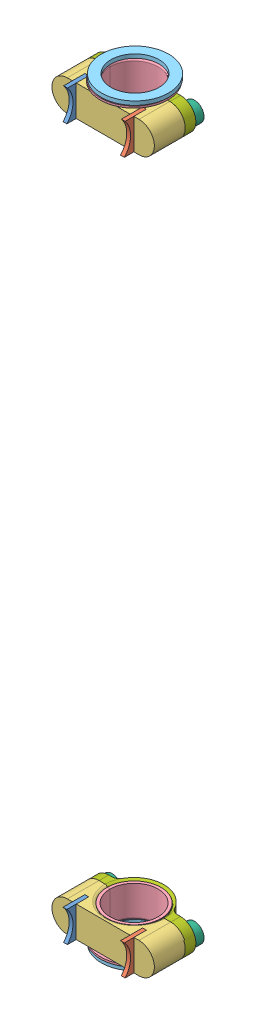
SolidWorks assembly PUTM-S-SF-RB-Mounting, configuration Domyślna. Lengths in mm.
Overall size (54.79 391.56 40.49).
20 component instances, 7 part files, 12 mates.
Components (placement in the parent):
- PUTM-S-SF-RB-laser1-1: PUTM-S-SF-RB-laser1 [Domyślna] at (-108.0802 185.4224 141.706) x (0.001057 0 -0.999999) z (0.999999 0 0.001057) size (11.34 16 2)
- PUTM-S-SF-RB-laser2-1: PUTM-S-SF-RB-laser2 [Domyślna] at (-78.009 192.7705 74.37) x (0 -1 0) z (-0.999999 0 -0.001057) size (16 11.45 2)
- PUTM-S-SF-RB-bearing_mount_low_v2-1: PUTM-S-SF-RB-bearing_mount_low_v2 [Domyślna] at (-94.0037 184.7705 69.3531) x (-0.999999 0 -0.001057) z (0 -1 0) size (53.3 16.5 16)
- PUTM-S-SF-RB-PCMF 252816.5 [SKF]-1: PUTM-S-SF-RB-PCMF 252816.5 [SKF] [Domyślna] at (-94 193.7767 69.8) x (0 -1 0) z (-0.001057 0 0.999999) size (16.5 35 17.5)
- PUTM-S-SF-RB-bearing_end-1: PUTM-S-SF-RB-bearing_end [Domyślna] at (-93.9995 195.7801 69.3) x (0 -1 0) z (-0.996102 0 -0.088209) size (2 35 35)
- PUTM-S-SF-RB-Bolt-1: PUTM-S-SF-RB-Bolt [Domyślna] at (-72.5894 184.7801 59.8226) x (-0.894549 0.446969 -0.000946) z (-0.446968 -0.89455 -0.000473) size (10 24 10)
- PUTM-S-SF-RB-PCMF 252816.5 [SKF]-2: PUTM-S-SF-RB-PCMF 252816.5 [SKF] [Domyślna] at (-94 193.7801 69.8) x (0 -1 0) z (0.001057 0 -0.999999) size (16.5 35 17.5)
- PUTM-S-SF-RB_bearing_mount_assembly-1: PUTM-S-SF-RB_bearing_mount_assembly [Domyślna] at (-46.3267 184.7801 69.3504) x (0.001057 0 -0.999999) z (0 -1 0) size (29.5 53.3 16)
  - PUTM-S-SF-RB-bearing_mount-1: PUTM-S-SF-RB-bearing_mount [Domyślna] at (-0.5 -47.6728 -8) size (15.5 53.3 16)
  - PUTM-S-SF-RB-Bolt-2: PUTM-S-SF-RB-Bolt [Domyślna] at (9.5 -69.0728 0) x (0 -0.0195 -0.99981) z (0 -0.99981 0.0195) size (10 24 10)
- PUTM-S-SF-RB-PCMF 252816.5 [SKF]-3: PUTM-S-SF-RB-PCMF 252816.5 [SKF] [Domyślna] at (-94 -193.7801 69.8) x (0 1 0) z (0.001057 0 -0.999999) size (16.5 35 17.5)
- PUTM-S-SF-RB-Bolt-2: PUTM-S-SF-RB-Bolt [Domyślna] at (-72.5894 -184.7801 59.8226) x (-0.894549 -0.446969 -0.000946) z (0.446968 -0.89455 0.000473) size (10 24 10)
- PUTM-S-SF-RB-laser1-2: PUTM-S-SF-RB-laser1 [Domyślna] at (-110.0802 -185.4224 141.7038) x (0.001057 0 -0.999999) z (-0.999999 0 -0.001057) size (11.34 16 2)
- PUTM-S-SF-RB-bearing_end-2: PUTM-S-SF-RB-bearing_end [Domyślna] at (-93.9995 -195.7801 69.3) x (0 1 0) z (0.996102 0 0.088209) size (2 35 35)
- PUTM-S-SF-RB_bearing_mount_assembly-2: PUTM-S-SF-RB_bearing_mount_assembly [Domyślna] at (-46.3267 -184.7801 69.3504) x (0.001057 0 -0.999999) z (0 -1 0) size (29.5 53.3 16)
  - PUTM-S-SF-RB-bearing_mount-1: PUTM-S-SF-RB-bearing_mount [Domyślna] at (-0.5 -47.6728 -8) size (15.5 53.3 16)
  - PUTM-S-SF-RB-Bolt-2: PUTM-S-SF-RB-Bolt [Domyślna] at (9.5 -69.0728 0) x (0 -0.0195 -0.99981) z (0 -0.99981 0.0195) size (10 24 10)
- PUTM-S-SF-RB-PCMF 252816.5 [SKF]-4: PUTM-S-SF-RB-PCMF 252816.5 [SKF] [Domyślna] at (-94 -193.7767 69.8) x (0 1 0) z (-0.001057 0 0.999999) size (16.5 35 17.5)
- PUTM-S-SF-RB-bearing_mount_low_v2-2: PUTM-S-SF-RB-bearing_mount_low_v2 [Domyślna] at (-94.0037 -184.7705 69.3531) x (0.999999 0 0.001057) z (0 1 0) size (53.3 16.5 16)
- PUTM-S-SF-RB-laser2-2: PUTM-S-SF-RB-laser2 [Domyślna] at (-80.009 -192.7705 74.3679) x (0 1 0) z (0.999999 0 0.001057) size (16 11.45 2)
Mates (geometry in assembly coordinates):
- Wspólnie76: coincident anti-aligned: plane of PUTM-S-SF-RB-bearing_mount_low_v2-1 through (-108.0037 192.7705 69.3383) normal (-0.999999 0 -0.001057); plane of PUTM-S-SF-RB-laser1-1 through (-108.0802 185.4224 141.706) normal (0.999999 0 0.001057)
- Wspólnie86: coincident anti-aligned: plane of PUTM-S-SF-RB-laser1-1 through (-113.0143 185.4224 79.333) normal (0.001057 0 -0.999999); plane of PUTM-S-SF-RB-bearing_mount_low_v2-1 through (-94.0143 192.7705 79.3531) normal (-0.001057 0 0.999999)
- Wspólnie87: coincident aligned: plane of PUTM-S-SF-RB-laser1-1 through (-110.0802 176.7705 141.7038) normal (0 -1 0); plane of PUTM-S-SF-RB-bearing_mount_low_v2-1 through (-94.0037 176.7705 69.3531) normal (0 -1 0)
- Wspólnie93: coincident anti-aligned: plane of PUTM-S-SF-RB-laser2-1 through (-80.009 192.7705 74.3679) normal (-0.999999 0 -0.001057); plane of PUTM-S-SF-RB-bearing_mount_low_v2-1 through (-80.0037 192.7705 69.3679) normal (0.999999 0 0.001057)
- Wspólnie94: coincident aligned: plane of PUTM-S-SF-RB-laser2-1 through (-80.009 176.7705 74.3679) normal (0 -1 0); plane of PUTM-S-SF-RB-bearing_mount_low_v2-1 through (-94.0037 176.7705 69.3531) normal (0 -1 0)
- Wspólnie95: coincident anti-aligned: plane of PUTM-S-SF-RB-laser2-1 through (-75.0143 192.7705 79.3732) normal (0.001057 0 -0.999999); plane of PUTM-S-SF-RB-bearing_mount_low_v2-1 through (-94.0143 192.7705 79.3531) normal (-0.001057 0 0.999999)
- Wspólnie79: coincident: plane of PUTM-S-SF-RB-PCMF 252816.5 [SKF]-2 through (-107.5 192.7801 69.7857) normal (-0.001057 0 0.999999); plane of PUTM-S-SF-RB-PCMF 252816.5 [SKF]-1 through (-107.5 192.7767 69.7857) normal (0.001057 0 -0.999999)
- Wspólnie96: coincident: plane of PUTM-S-SF-RB-PCMF 252816.5 [SKF]-2 through (-80.5 193.7801 69.8143) normal (0 1 0); plane of PUTM-S-SF-RB-bearing_end-1 through (-93.9995 193.7801 69.3) normal (0 -1 0)
- Koncentryczne9: concentric aligned: cylinder of PUTM-S-SF-RB_bearing_mount_assembly-1/PUTM-S-SF-RB-bearing_mount-1 through (-72.5942 184.7801 64.3226) axis (-0.001057 0 0.999999) radius 3; cylinder of PUTM-S-SF-RB-Bolt-1 through (-72.5894 184.7801 59.8226) axis (-0.001057 0 0.999999) radius 3
- Wspólnie26: coincident anti-aligned: plane of PUTM-S-SF-RB_bearing_mount_assembly-1/PUTM-S-SF-RB-bearing_mount-1 through (-93.9942 192.7801 64.3) normal (0.001057 0 -0.999999); plane of PUTM-S-SF-RB-Bolt-1 through (-77.0669 187.015 64.3179) normal (-0.001057 0 0.999999)
- Wspólnie78: coincident aligned: plane of PUTM-S-SF-RB-PCMF 252816.5 [SKF]-2 through (-80.5 192.7801 69.8143) normal (-0.001057 0 0.999999); plane of PUTM-S-SF-RB_bearing_mount_assembly-1/PUTM-S-SF-RB-bearing_mount-1 through (-78.5 176.7801 69.8164) normal (-0.001057 0 0.999999)
- Wspólnie92: coincident aligned: plane of PUTM-S-SF-RB-PCMF 252816.5 [SKF]-2 through (-76.5 192.7801 69.8185) normal (0 -1 0); circle of PUTM-S-SF-RB_bearing_mount_assembly-1/PUTM-S-SF-RB-bearing_mount-1
